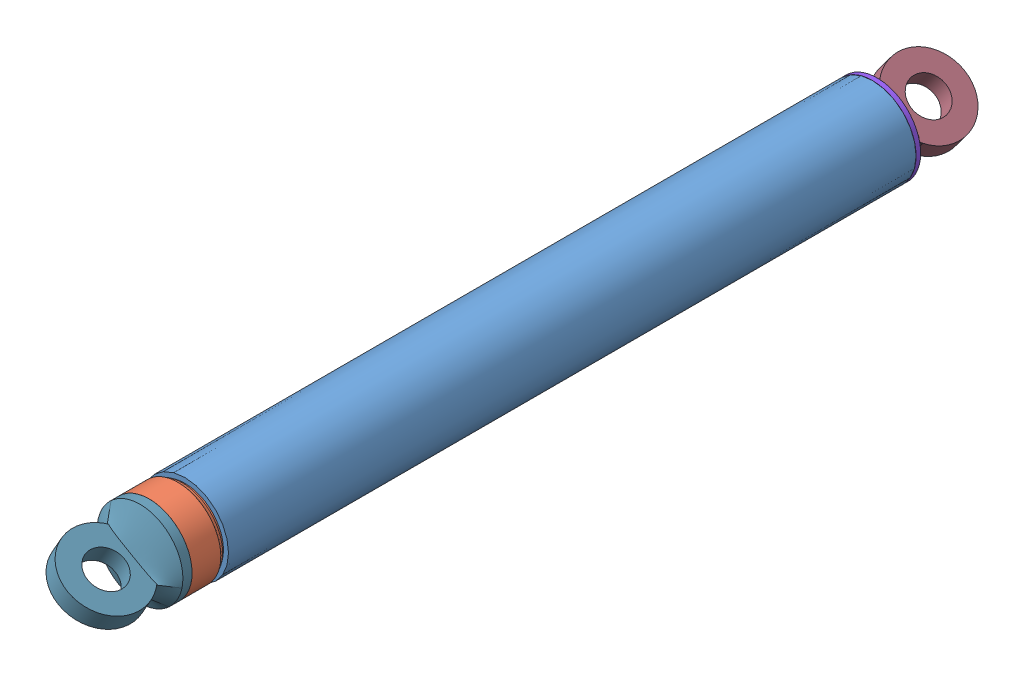
SolidWorks assembly hidrolik silindir, configuration Varsayılan. Lengths in mm.
Overall size (131.23 131.23 980.28).
14 component instances, 14 part files, 26 mates.
Components (placement in the parent):
- silindir-1: silindir [Varsayılan] at (-76.0241 11.3159 0) size (95 100 750)
- içteki ikinci tutucu-1: içteki ikinci tutucu [Varsayılan] at (-76.0241 11.3159 422.2792) x (0 0 1) z (0.616399 -0.787434 0) size (44 93.48 93.48)
- içteki ilk tutucu-1: içteki ilk tutucu [Varsayılan] at (-76.0241 11.3159 358.8679) x (0 0 1) z (0.591851 0.806047 0) size (49 80 80)
- keçe 1-1: keçe 1 [Varsayılan] at (-76.0241 11.3159 351.9589) x (0 0 -1) z (1 0 0) size (1.36 69.66 69.66)
- keçe 2-1: keçe 2 [Varsayılan] at (-76.0241 11.3159 371.6768) x (0 0 1) z (-1 0 0) size (5.48 80 80)
- keçe 3-1: keçe 3 [Varsayılan] at (-76.0241 11.3159 326.5892) x (0 0 -1) z (1 0 0) size (2.92 80 80)
- saft-1: saft [Varsayılan] at (-76.0241 11.3159 -3.2793) x (0.475086 -0.87994 0) z (0 0 1) size (56 56 750)
- arka kapak tutucu-1: arka kapak tutucu [Varsayılan] at (-76.0241 11.3159 -309.3353) x (0 0 1) z (0.894804 0.446459 0) size (33.16 95 95)
- keçe 1 dış-1: keçe 1 dış [Varsayılan] at (-76.0241 11.3159 -320.5122) x (0 0 1) z (0.970169 -0.242431 0) size (2.86 66 66)
- keçe 2 dış-1: keçe 2 dış [Varsayılan] at (-76.0241 11.3159 -436.9634) x (0 0 -1) z (1 0 0) size (4.74 66 66)
- keçe 3 dış-1: keçe 3 dış [Varsayılan] at (-76.0241 11.3159 -416.1521) x (0 0 -1) z (1 0 0) size (4.42 66 66)
- keçe 4 dış-1: keçe 4 dış [Varsayılan] at (-76.0241 11.3159 -294.5344) x (0 0 1) z (0.993532 0.113555 0) size (4 80 80)
- rot kolu dış-2: rot kolu dış [Varsayılan<As Machined>] at (-76.0241 11.3159 -430.2793) x (-0.801408 0.598118 0) z (0.598118 0.801408 0) size (84 94 56.1)
- rot kolu-3: rot kolu [Varsayılan] at (-76.0241 11.3159 466) x (0.86927 -0.494338 0) z (0.494338 0.86927 0) size (93.6 94 93.6)
Mates (geometry in assembly coordinates):
- Concentric1: concentric aligned: cylinder of silindir-1 through (-76.0241 11.3159 375) axis (0 0 -1) radius 40; cylinder of içteki ilk tutucu-1 through (-76.0241 11.3159 292.8415) axis (0 0 -1) radius 39.7949
- Distance1: distance = 5 mm aligned: plane of içteki ilk tutucu-1 through (-108.1006 34.8685 370) normal (0 0 1); plane of silindir-1 through (-76.0241 11.3159 375) normal (0 0 1)
- Coincident2: coincident anti-aligned: plane of içteki ikinci tutucu-1 through (-56.5686 26.5455 370) normal (0 0 -1); plane of içteki ilk tutucu-1 through (-108.1006 34.8685 370) normal (0 0 1)
- Concentric2: concentric aligned: cylinder of silindir-1 through (-76.0241 11.3159 375) axis (0 0 -1) radius 40; cylinder of içteki ikinci tutucu-1 through (-76.0241 11.3159 340.1554) axis (0 0 -1) radius 42
- Concentric5: concentric anti-aligned: cylinder of içteki ilk tutucu-1 through (-76.0241 11.3159 292.8415) axis (0 0 -1) radius 35; cylinder of keçe 3-1 through (-76.0241 11.3159 401.3465) axis (0 0 1) radius 35
- Coincident5: coincident anti-aligned: plane of içteki ilk tutucu-1 through (-104.2357 32.0307 349.0046) normal (0 0 -1); plane of keçe 3-1 through (-76.0241 -28.6841 349.0046) normal (0 0 1)
- Concentric6: concentric aligned: cylinder of içteki ilk tutucu-1 through (-76.0241 11.3159 292.8415) axis (0 0 -1) radius 38; cylinder of keçe 2-1 through (-76.0241 11.3159 288.4681) axis (0 0 -1) radius 38
- Coincident6: coincident anti-aligned: plane of içteki ilk tutucu-1 through (-106.6539 33.8062 339.2511) normal (0 0 -1); plane of keçe 2-1 through (-76.0241 -26.6841 339.2511) normal (0 0 1)
- Concentric7: concentric anti-aligned: cylinder of içteki ilk tutucu-1 through (-76.0241 11.3159 292.8415) axis (0 0 -1) radius 34.832; cylinder of keçe 1-1 through (-76.0241 11.3159 427.5347) axis (0 0 1) radius 34.83
- Coincident7: coincident anti-aligned: plane of içteki ilk tutucu-1 through (-104.1003 31.9313 325.9) normal (0 0 -1); plane of keçe 1-1 through (-76.0241 -23.5141 325.9) normal (0 0 1)
- Concentric8: concentric aligned: cylinder of silindir-1 through (-76.0241 11.3159 375) axis (0 0 -1) radius 40; cylinder of saft-1 through (-76.0241 11.3159 371.7207) axis (0 0 -1) radius 28
- Coincident9: coincident anti-aligned: plane of silindir-1 through (-76.0241 11.3159 -375) normal (0 0 -1); plane of arka kapak tutucu-1 through (-97.2308 53.8191 -375) normal (0 0 1)
- Concentric11: concentric aligned: cylinder of silindir-1 through (-76.0241 11.3159 375) axis (0 0 -1) radius 40; cylinder of arka kapak tutucu-1 through (-76.0241 11.3159 -390.9135) axis (0 0 -1) radius 40
- Distance2: distance = 0 mm: cylinder of keçe 1 dış-1 through (-76.0241 11.3159 -396.837) axis (0 0 -1) radius 33; cylinder of arka kapak tutucu-1 through (-76.0241 11.3159 -390.9135) axis (0 0 -1) radius 33
- Coincident10: coincident anti-aligned: plane of arka kapak tutucu-1 through (-89.4178 38.16 -379.0604) normal (0 0 1); plane of keçe 1 dış-1 through (-68.7511 40.4209 -379.0604) normal (0 0 -1)
- Concentric18: concentric anti-aligned: cylinder of arka kapak tutucu-1 through (-76.0241 11.3159 -390.9135) axis (0 0 -1) radius 33; cylinder of keçe 2 dış-1 through (-76.0241 11.3159 -355.6581) axis (0 0 1) radius 33
- Coincident11: coincident aligned: plane of arka kapak tutucu-1 through (-89.4178 38.16 -371.7643) normal (0 0 1); plane of keçe 2 dış-1 through (-76.0241 -21.6841 -371.7643) normal (0 0 1)
- Concentric19: concentric anti-aligned: cylinder of arka kapak tutucu-1 through (-76.0241 11.3159 -390.9135) axis (0 0 -1) radius 31.5; cylinder of keçe 3 dış-1 through (-76.0241 11.3159 -337.0295) axis (0 0 1) radius 33
- Coincident12: coincident aligned: plane of arka kapak tutucu-1 through (-89.4178 38.16 -353.3997) normal (0 0 1); plane of keçe 3 dış-1 through (-76.0241 -20.1841 -353.3997) normal (0 0 1)
- Concentric23: concentric aligned: cylinder of arka kapak tutucu-1 through (-76.0241 11.3159 -390.9135) axis (0 0 -1) radius 37; cylinder of keçe 4 dış-1 through (-76.0241 11.3159 -376.1126) axis (0 0 -1) radius 36.999
- Coincident15: coincident anti-aligned: plane of arka kapak tutucu-1 through (-93.8824 47.1081 -362.3685) normal (0 0 1); plane of keçe 4 dış-1 through (-76.0241 11.3159 -362.3685) normal (0 0 -1)
- LimitDistance1: limit distance = 0 mm anti-aligned: plane of saft-1 through (-76.0241 11.3159 371.7207) normal (0 0 1); plane of içteki ikinci tutucu-1 through (-71.7267 14.6799 371.7207) normal (0 0 -1)
- Coincident21: coincident anti-aligned: plane of içteki ikinci tutucu-1 through (-39.2185 40.1271 414) normal (0 0 1); plane of rot kolu-3 through (-76.0241 11.3159 414) normal (0 0 -1)
- Concentric25: concentric anti-aligned: cylinder of içteki ikinci tutucu-1 through (-76.0241 11.3159 340.1554) axis (0 0 -1) radius 46.7411; cylinder of rot kolu-3 through (-76.0241 11.3159 414) axis (0 0 1) radius 46.75
- Coincident22: coincident anti-aligned: plane of saft-1 through (-76.0241 11.3159 -378.2793) normal (0 0 -1); plane of rot kolu dış-2 through (-76.0241 11.3159 -378.2793) normal (0 0 1)
- Concentric26: concentric aligned: cylinder of saft-1 through (-76.0241 11.3159 371.7207) axis (0 0 -1) radius 28; cylinder of rot kolu dış-2 through (-76.0241 11.3159 -378.2793) axis (0 0 -1) radius 28
